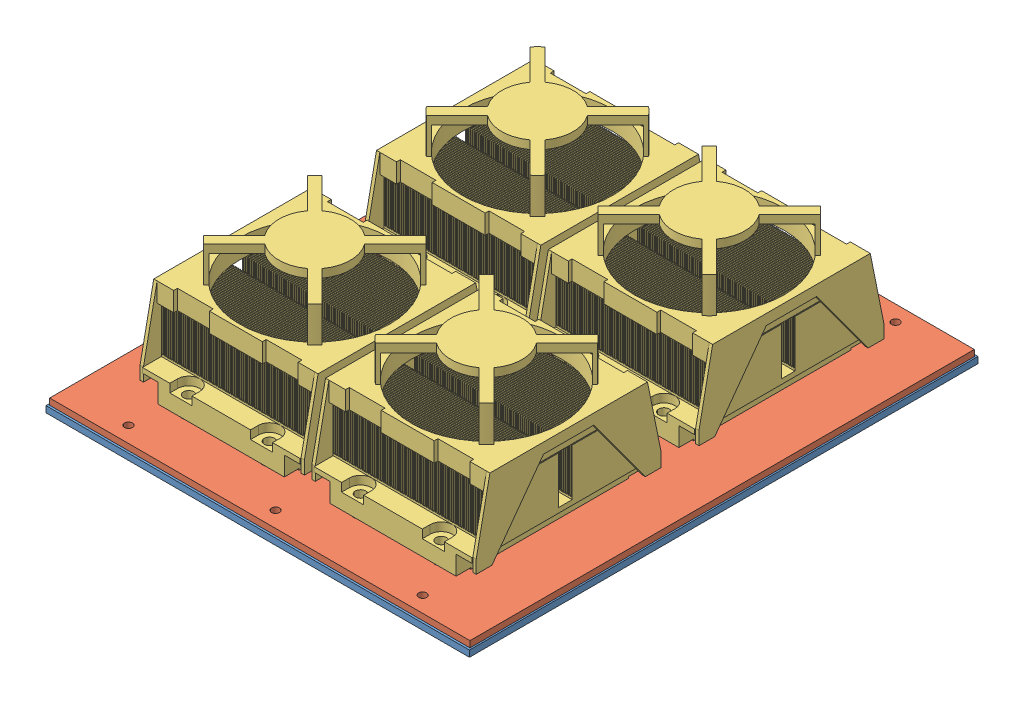
SolidWorks assembly Peltier Assembly 2.0, configuration Default. Lengths in mm.
Overall size (201.5 67.32 242).
6 component instances, 3 part files, 18 mates.
Components (placement in the parent):
- Cold plate 2.0-1: Cold plate 2.0 [Default] at (-100.75 0 -221.75) x (0 0 1) z (0 1 0) size (242 201.5 3)
- Acrylic seperator-1: Acrylic seperator [Default] at (100 3 220) x (0 0 -1) z (0 1 0) size (240 200 3)
- Heatsink 3.0-5: Heatsink 3.0 [Default] at (40.875 6 -53) size (78.2 61.32 89)
- Heatsink 3.0-6: Heatsink 3.0 [Default] at (-40.875 6 -53) size (78.2 61.32 89)
- Heatsink 3.0-7: Heatsink 3.0 [Default] at (40.875 6 53) size (78.2 61.32 89)
- Heatsink 3.0-8: Heatsink 3.0 [Default] at (-40.875 6 53) size (78.2 61.32 89)
Mates (geometry in assembly coordinates):
- Coincident31: coincident anti-aligned: plane of Cold plate 2.0-1 through (0 0 0) normal (0 -1 0)
- Symmetric1: symmetric aligned: plane of Cold plate 2.0-1 through (100.75 3 -121) normal (1 0 0); plane of Cold plate 2.0-1 through (-100.75 3 -121) normal (-1 0 0)
- Symmetric2: symmetric aligned: plane of Cold plate 2.0-1 through (100.75 3 -121) normal (0 0 -1); plane of Cold plate 2.0-1 through (100.75 3 121) normal (0 0 1)
- Coincident33: coincident anti-aligned: plane of Cold plate 2.0-1 through (0 3 0) normal (0 1 0); plane of Acrylic seperator-1 through (0 3 0) normal (0 -1 0)
- Distance1: distance = 43.35 mm: cylinder of Heatsink 3.0-5 through (21.675 18.15 -93.75) axis (0 -1 0) radius 2.5; cylinder of Heatsink 3.0-6 through (-21.675 18.15 -93.75) axis (0 -1 0) radius 2.5
- Coincident39: coincident aligned: plane of Heatsink 3.0-5 through (3.375 18.15 -97.5) normal (0 0 -1); plane of Heatsink 3.0-6 through (-78.375 18.15 -97.5) normal (0 0 -1)
- Width1: width anti-aligned: plane of Heatsink 3.0-5 through (3.375 18.15 -97.5) normal (0 0 -1); plane of Heatsink 3.0-5 through (3.375 18.15 -8.5) normal (0 0 1)
- Width2: width anti-aligned: plane of Heatsink 3.0-5 through (78.375 18.15 -8.5) normal (1 0 0); plane of Cold plate 2.0-1 through (-78.375 18.15 -8.5) normal (-1 0 0); plane of Heatsink 3.0-6 through (-100.75 3 -121) normal (-1 0 0); plane of Cold plate 2.0-1 through (100.75 3 -121) normal (1 0 0)
- Distance2: distance = 43.35 mm: cylinder of Heatsink 3.0-8 through (-21.675 18.15 93.75) axis (0 -1 0) radius 2.5; cylinder of Heatsink 3.0-7 through (21.675 18.15 93.75) axis (0 -1 0) radius 2.5
- Coincident40: coincident aligned: plane of Heatsink 3.0-7 through (3.375 18.15 97.5) normal (0 0 1); plane of Heatsink 3.0-8 through (-78.375 18.15 97.5) normal (0 0 1)
- Width3: width aligned: plane of Heatsink 3.0-8 through (-78.375 18.15 97.5) normal (0 0 1); plane of Heatsink 3.0-8 through (-78.375 18.15 8.5) normal (0 0 -1)
- Width4: width aligned: plane of Heatsink 3.0-8 through (-78.375 18.15 97.5) normal (-1 0 0); plane of Cold plate 2.0-1 through (78.375 18.15 97.5) normal (1 0 0); plane of Heatsink 3.0-7 through (-100.75 3 -121) normal (-1 0 0); plane of Cold plate 2.0-1 through (100.75 3 -121) normal (1 0 0)
- Coincident41: coincident aligned: plane of Heatsink 3.0-5 through (40.875 6 -53) normal (0 -1 0); plane of Heatsink 3.0-6 through (-40.875 6 -53) normal (0 -1 0)
- Coincident42: coincident aligned: plane of Heatsink 3.0-7 through (40.875 6 53) normal (0 -1 0); plane of Heatsink 3.0-8 through (-40.875 6 53) normal (0 -1 0)
- Coincident43: coincident aligned: plane of Heatsink 3.0-5 through (40.875 6 -53) normal (0 -1 0); plane of Heatsink 3.0-7 through (40.875 6 53) normal (0 -1 0)
- Coincident44: coincident anti-aligned: plane of Acrylic seperator-1 through (0 6 0) normal (0 1 0); plane of Heatsink 3.0-5 through (40.875 6 -53) normal (0 -1 0)
- Width5: width anti-aligned: plane of Acrylic seperator-1 through (-100 6 -120) normal (0 0 -1); plane of Cold plate 2.0-1 through (-100 6 120) normal (0 0 1); plane of Acrylic seperator-1 through (100.75 3 121) normal (0 0 1); plane of Cold plate 2.0-1 through (100.75 3 -121) normal (0 0 -1)
- Width6: width anti-aligned: plane of Acrylic seperator-1 through (100 6 120) normal (1 0 0); plane of Cold plate 2.0-1 through (-100 6 120) normal (-1 0 0); plane of Acrylic seperator-1 through (-100.75 3 -121) normal (-1 0 0); plane of Cold plate 2.0-1 through (100.75 3 -121) normal (1 0 0)
